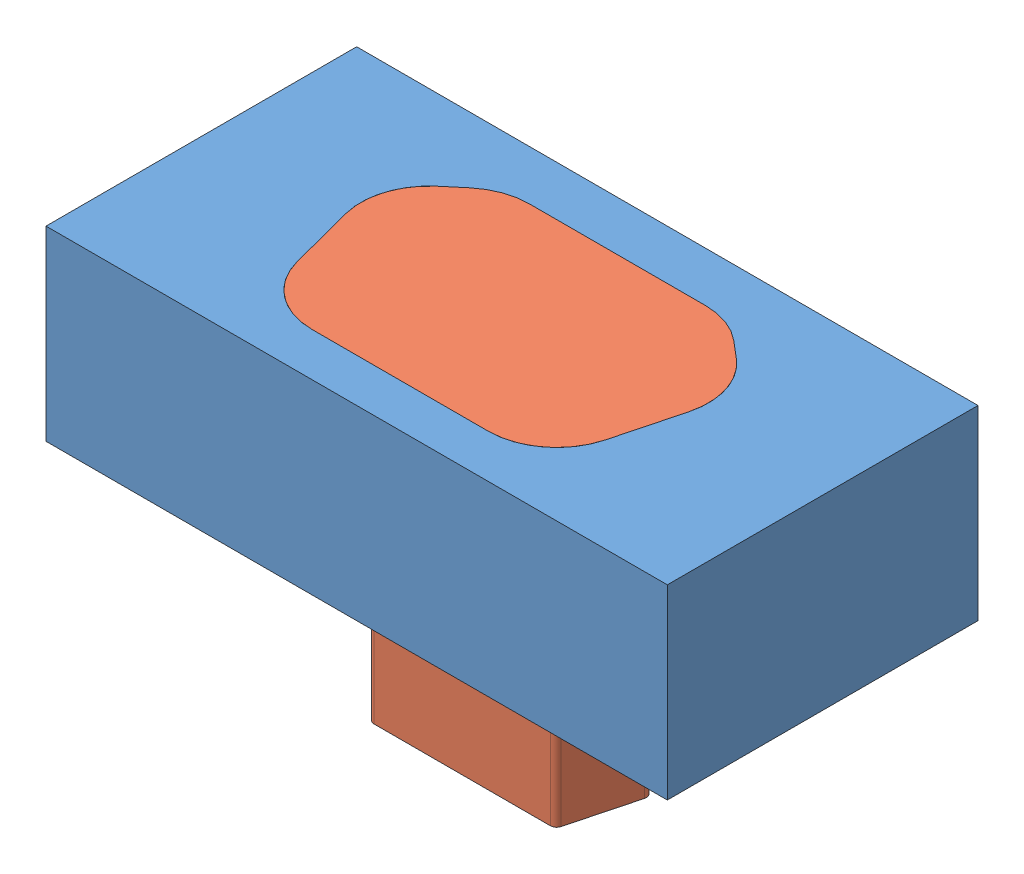
SolidWorks assembly Assem3, configuration Default. Lengths in mm.
Overall size (100 60 50).
2 component instances, 2 part files, 3 mates.
Components (placement in the parent):
- tool punch HOLDER 2-1: tool punch HOLDER 2 [Default] at (50.3446 21.2528 80.7139) size (100 30 50)
- tool punch 2-1: tool punch 2 [Default] at (50.3446 -8.7472 80.7139) size (55.95 60 35)
Mates (geometry in assembly coordinates):
- Coincident2: coincident anti-aligned: plane of tool punch HOLDER 2-1 through (50.3446 41.2528 73.7139) normal (0 0 1); plane of tool punch 2-1 through (36.1605 41.2528 73.7139) normal (0 0 -1)
- Coincident3: coincident anti-aligned: plane of tool punch HOLDER 2-1 through (34.3937 41.2528 84.901) normal (0.967231 0 -0.253898); plane of tool punch 2-1 through (35.1987 41.2528 87.9678) normal (-0.967231 0 0.253898)
- Coincident4: coincident anti-aligned: plane of tool punch HOLDER 2-1 through (50.3446 41.2528 80.7139) normal (0 1 0); plane of tool punch 2-1 through (64.5286 41.2528 74.7139) normal (0 -1 0)
